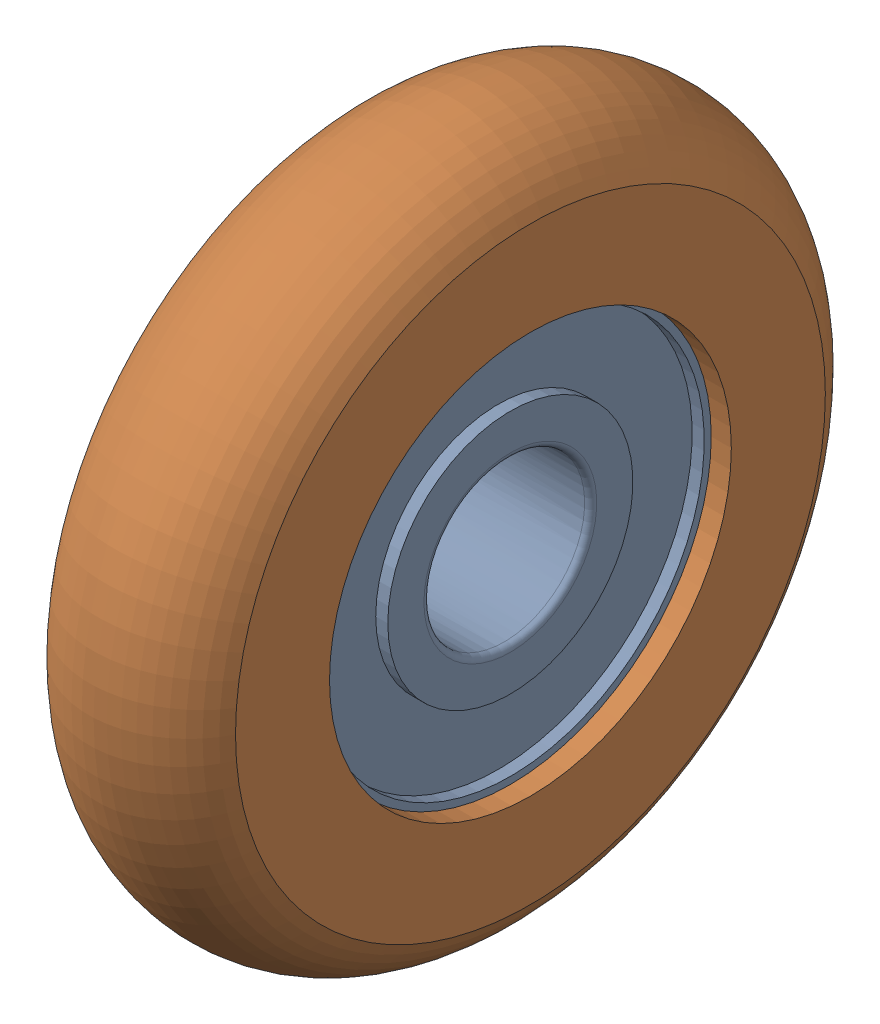
SolidWorks assembly MISUMI_ERBS35, configuration Default. Lengths in mm.
Overall size (9 35 35).
2 component instances, 2 part files, 3 mates.
Components (placement in the parent):
- BEARING_MISUMI_ERBS35-1: BEARING_MISUMI_ERBS35 [Default] at origin size (7 22 22)
- RESIN_MISUMI_ERBS35-1: RESIN_MISUMI_ERBS35 [Default] at (1 0 0) size (9 35 35)
Mates (geometry in assembly coordinates):
- Concentric1: concentric aligned: cylinder of BEARING_BaseModel20240727221545-1 through (-7 0 0) axis (-1 0 0) radius 11; cylinder of RESIN_BaseModel20240727221545-1 through (-8 0 0) axis (-1 0 0) radius 11
- Coincident1: coincident anti-aligned: plane of BEARING_BaseModel20240727221545-1 through (0 11 0) normal (1 0 0); plane of RESIN_BaseModel20240727221545-1 through (0 10 0) normal (-1 0 0)
- Coincident2: coincident aligned: plane of RESIN_BaseModel20240727221545-1 through (1 0 0) normal (0 0 1)
